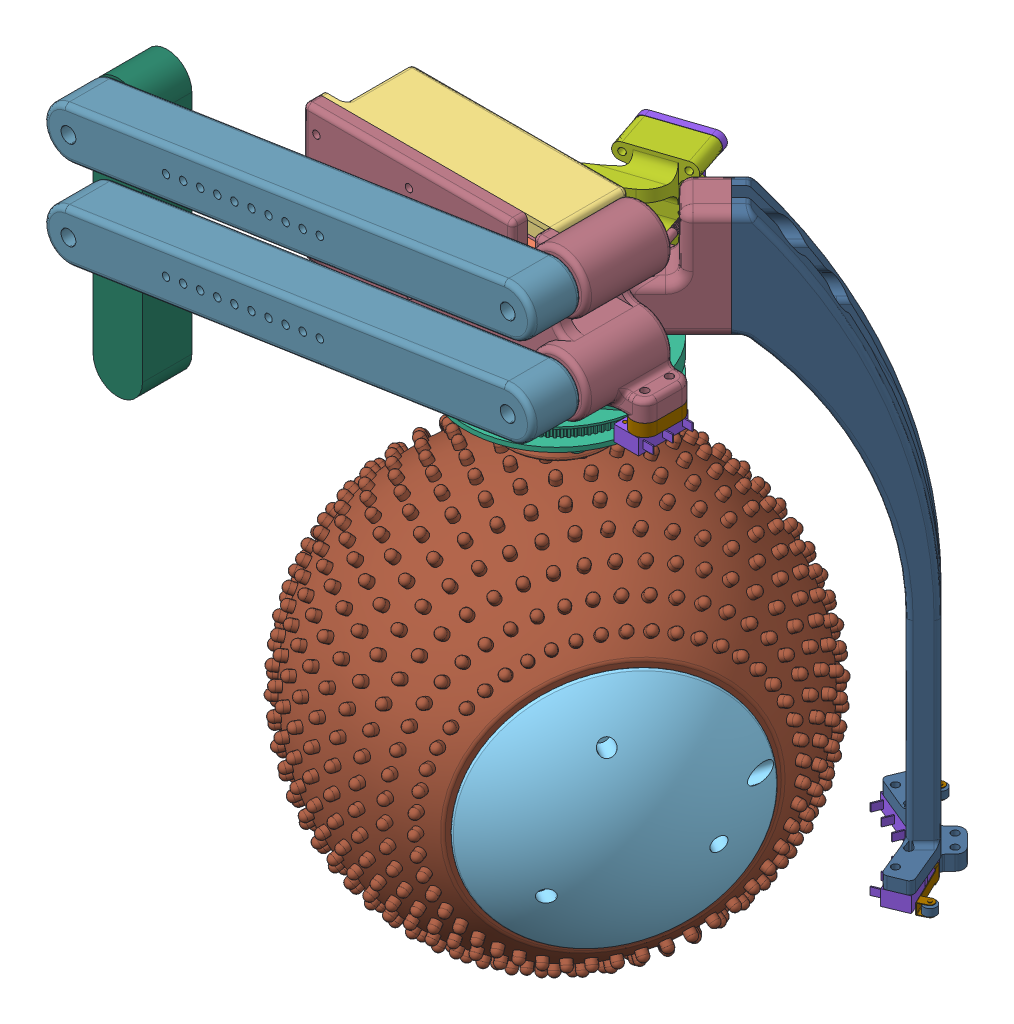
SolidWorks assembly _OmniWheel, configuration Default. Lengths in mm.
Overall size (256.7 285.35 230.93).
45 component instances, 31 part files, 111 mates.
Components (placement in the parent):
- 10mmThreadedRod-1: 10mmThreadedRod [Default] at (69.9224 -131.1915 -77.1045) x (0.033468 -0.997752 -0.058051) z (0.498338 0.067008 -0.864389) size (9.53 70 9.53)
- arduino-1: arduino [Valor predeterminado] at (146.3646 24.3085 -21) x (-1 0 0) z (0 0 -1) size (45.18 4.5 17.78)
- DriveMotor-1: DriveMotor [Default] at (151.3581 -131.1915 -30.1552) x (-0.264151 0.848701 0.458182) z (0.423893 0.528873 -0.735261) size (25 86.5 25)
- hollowThreadedNut-1: hollowThreadedNut [Default] at (108.5177 -131.1915 -54.8536) x (-0.092382 -0.982745 0.16024) z (0.490843 -0.184963 -0.851388) size (16.17 2.5 14)
- L298N Motor Driver arduino-1: L298N Motor Driver arduino [Default] at (94.2046 24.5585 -9.5) x (0 1 0) z (-1 0 0) size (43.5 26 43.5)
- n20 m4x55 encoder v2-1: n20 m4x55 encoder v2 [Default] at (132.885 2.6585 -90.2245) x (-0.316146 0 -0.948711) z (0 -1 0) size (12 10 42.21)
- slip_ring-1: slip_ring [Default] at (142.9546 -25.9415 -35) x (0.999063 0 0.043268) z (-0.043268 0 0.999063) size (23.5 17.5 23.5)
- switch_body-1: switch_body [Default] at (195.9546 -11.0665 -25) x (0 0 -1) z (0 1 0) size (20 14 6.25)
- switch_lever-1: switch_lever [Default] at (185.7475 -11.0665 -26.5353) x (0.019708 0 -0.999806) z (0 1 0) size (20 8.75 6)
- switch_wheel-1: switch_wheel [Default] at (182.2858 -10.9415 -34.8551) x (-0.999947 0 -0.010277) z (0 1 0) size (5 5 3)
- sphere_wheel-1: sphere_wheel [Default] at (142.9546 -131.1915 -35) x (-0.866337 0 -0.499461) z (0.492131 0.170683 -0.853624) size (125.5 168 168)
- motorMount-1: motorMount [Default] at (128.855 -131.1915 -43.1287) x (0.446555 -0.447916 -0.77457) z (-0.223716 -0.894076 0.388046) size (31.75 83.44 31.75)
- hollowThreadedNut-2: hollowThreadedNut [Default] at (121.686 -131.1915 -47.2618) x (-0.092382 -0.982745 0.16024) z (0.490843 -0.184963 -0.851388) size (16.17 2.5 14)
- hollowThreadedNut-4: hollowThreadedNut [Default] at (69.0994 -131.1915 -77.579) x (0.01495 -0.999552 -0.025931) z (0.499237 0.029932 -0.865948) size (16.17 2.5 14)
- hollowThreadedNut-5: hollowThreadedNut [Default] at (85.1266 -131.1915 -68.339) x (0.24973 -0.866025 -0.433168) z (0.432546 0.5 -0.75027) size (16.17 2.5 14)
- suspension_mount-1: suspension_mount [Default] at (142.9546 -2.9415 -35) x (0 0 1) z (0 1 0) size (77.43 128.5 61.17)
- suspension_bar-1: suspension_bar [Default] at (177.9546 45.0585 10) x (0.988637 0.150325 0) z (0 0 1) size (200 20 20)
- suspension_mount_body-1: suspension_mount_body [Default] at origin size (20 111.88 20)
- bearing2-1: bearing2 [Default] at (104.4026 -131.1915 -57.226) x (0.296277 0.805059 -0.513906) z (0.402095 -0.593194 -0.697452) size (25 7 25)
- Wheel_cap-1: Wheel_cap [Default] at (107.4348 -131.1915 -55.4779) x (0.08525 -0.985326 -0.147869) z (0.492131 0.170683 -0.853624) size (59.5 22.5 59.5)
- washer1-1: washer1 [Default] at (99.0963 -131.1915 -60.2852) x (-0.362018 -0.68894 0.627937) z (0.344098 -0.724818 -0.596854) size (25 2.25 25)
- SpongeRing-1: SpongeRing [Default] at (94.0066 -131.1915 -63.2195) x (-0.866337 0 -0.499461) z (0.488344 -0.20981 -0.847054) size (14 51.5 51.5)
- wheel_arm-1: wheel_arm [Default] at (85.7764 -131.1915 -67.9644) x (-0.866337 0 -0.499461) z (0.499461 0 -0.866337) size (108.38 170.79 80.42)
- suspension_bar-3: suspension_bar [Default] at (177.9546 9.0585 10) x (0.988637 0.150325 0) z (0 0 1) size (200 20 20)
- suspension_mount_lid-1: suspension_mount_lid [Default] at (117.9546 24.5585 -39) x (1 0 0) z (0 0 -1) size (96 55 30)
- bearing3-1: bearing3 [Default] at (142.9546 -10.1915 -35) x (0.997463 0 -0.071184) z (0 -1 0) size (28.5 28.5 9.5)
- 10mmThreadedRod-2: 10mmThreadedRod [short] at (142.9546 12.0585 -35) x (0.211057 0 0.977474) z (-0.977474 0 0.211057) size (9.53 36 9.53)
- hollowThreadedNut-6: hollowThreadedNut [Default] at (142.9546 15.3085 -35) x (-0.864079 0 0.503356) z (0.503356 0 0.864079) size (16.17 2.5 14)
- hollowThreadedNut-7: hollowThreadedNut [Default] at (142.9546 -4.1915 -35) x (-0.864079 0 0.503356) z (0.503356 0 0.864079) size (16.17 2.5 14)
- hollowThreadedNut-8: hollowThreadedNut [Default] at (142.9546 -16.1915 -35) x (-0.864079 0 0.503356) z (0.503356 0 0.864079) size (16.17 2.5 14)
- wheel_cap_2-1: wheel_cap_2 [Default] at (142.738 -131.1915 -35.1249) x (0.866337 0 0.499461) z (-0.08525 0.985326 0.147869) size (17.75 96.67 96.67)
- large_timing_pully-1: large_timing_pully [Default] at (142.9546 -15.9415 -35) x (-0.866337 0 -0.499461) z (0.499461 0 -0.866337) size (73.67 25.42 73.67)
- micro_gear_motor_casing_A-1: micro_gear_motor_casing_A [Default] at (132.8625 10.1585 -90.2212) x (-0.316146 0 -0.948711) z (0.948711 0 -0.316146) size (33.5 37 49.25)
- micro_gear_motor_casing_B-1: micro_gear_motor_casing_B [Default] at (130.4123 10.1585 -97.5737) x (-0.948711 0 0.316146) z (-0.316146 0 -0.948711) size (28.5 37.25 3)
- switch_spacer-1: switch_spacer [Default] at (193.4546 -5.4415 -25) x (0 0 -1) z (1 0 0) size (20 5 10)
- sensorArray_frame-1: sensorArray_frame [Default] at (178.3099 19.5585 -70.3553) x (-0.707107 0 0.707107) z (-0.707107 0 -0.707107) size (67.99 233.5 54.5)
- switch_body-2: switch_body [Default] at (200.7456 -188.5665 -113.7167) x (-0.92388 0 -0.382683) z (0 -1 0) size (20 14 6.25)
- switch_lever-2: switch_lever [Default] at (204.6761 -188.5665 -125.3908) x (-0.810364 0 -0.585927) z (0 -1 0) size (20 8.75 6)
- switch_wheel-2: switch_wheel [Default] at (200.1146 -188.5665 -133.1622) x (0.999993 0 -0.003676) z (0 -1 0) size (5 5 3)
- switch_body-3: switch_body [Default] at (221.6713 -188.5665 -92.791) x (0.382683 0 0.92388) z (0 1 0) size (20 14 6.25)
- switch_lever-3: switch_lever [Default] at (232.2619 -188.5665 -95.6971) x (0.439028 0 0.898473) z (0 1 0) size (20 8.75 6)
- switch_wheel-3: switch_wheel [Default] at (239.1409 -188.5665 -89.8762) x (-0.999993 0 -0.003746) z (0 1 0) size (5 5 3)
- 1375K107_MXL SERIES TIMING BELT PULLEY-1: 1375K107_MXL SERIES TIMING BELT PULLEY [1375K107] at (132.8625 -15.5518 -90.2212) x (0 -1 0) z (0 0 1) size (14.3 13.5 13.5)
- 90725A020_ZINC-PLATED STEEL HIGH HEX NUT-1: 90725A020_ZINC-PLATED STEEL HIGH HEX NUT [90725A020] at (144.7207 9.5585 -87.0579) x (0.900076 -0.316068 -0.299939) z (-0.299857 -0.948736 0.099924) size (5.5 3.39 6.35)
- 91290A130_BLACK-OXIDE CLASS 12.9 SOCKET HEAD CAP SCREW-1: 91290A130_BLACK-OXIDE CLASS 12.9 SOCKET HEAD CAP SCREW [91290A130] at (142.4135 9.5585 -93.9816) x (-0.851007 -0.442001 0.283587) z (-0.316146 0 -0.948711) size (5.5 5.5 33.26)
Mates (geometry in assembly coordinates):
- Concentric1: concentric aligned: cylinder of DriveMotor-1 through (195.1081 -131.1915 -4.9325) axis (-0.866337 0 -0.499461) radius 12.5; cylinder of sphere_wheel-1 through (206.1972 -131.1915 1.4606) axis (-0.866337 0 -0.499461) radius 25
- Concentric2: concentric aligned: cylinder of DriveMotor-1 through (171.717 -131.1915 -18.4179) axis (-0.866337 0 -0.499461) radius 12.2; cylinder of motorMount-1 through (181.8869 -131.1915 -12.5547) axis (-0.866337 0 -0.499461) radius 12.7
- Concentric4: concentric aligned: cylinder of 10mmThreadedRod-1 through (13.6105 -131.1915 -109.5695) axis (0.866337 0 0.499461) radius 4.7625; cylinder of motorMount-1 through (109.6006 -131.1915 -54.2292) axis (0.866337 0 0.499461) radius 4.7625
- Concentric5: concentric aligned: cylinder of 10mmThreadedRod-1 through (13.6105 -131.1915 -109.5695) axis (0.866337 0 0.499461) radius 4.7625; cylinder of hollowThreadedNut-1 through (107.4348 -131.1915 -55.4779) axis (0.866337 0 0.499461) radius 5
- Concentric6: concentric aligned: cylinder of 10mmThreadedRod-1 through (13.6105 -131.1915 -109.5695) axis (0.866337 0 0.499461) radius 4.7625; cylinder of hollowThreadedNut-2 through (120.6031 -131.1915 -47.8861) axis (0.866337 0 0.499461) radius 5
- Coincident1: coincident anti-aligned: plane of motorMount-1 through (120.6031 -131.1915 -47.8861) normal (0.866337 0 0.499461); plane of hollowThreadedNut-2 through (120.6031 -131.1915 -47.8861) normal (-0.866337 0 -0.499461)
- Coincident2: coincident anti-aligned: plane of hollowThreadedNut-1 through (109.6006 -131.1915 -54.2292) normal (0.866337 0 0.499461); plane of motorMount-1 through (109.6006 -131.1915 -54.2292) normal (-0.866337 0 -0.499461)
- Concentric9: concentric aligned: cylinder of 10mmThreadedRod-1 through (13.6105 -131.1915 -109.5695) axis (0.866337 0 0.499461) radius 4.7625; cylinder of hollowThreadedNut-4 through (68.0165 -131.1915 -78.2033) axis (0.866337 0 0.499461) radius 5
- Concentric10: concentric aligned: cylinder of 10mmThreadedRod-1 through (13.6105 -131.1915 -109.5695) axis (0.866337 0 0.499461) radius 4.7625; cylinder of hollowThreadedNut-5 through (84.0437 -131.1915 -68.9633) axis (0.866337 0 0.499461) radius 5
- Concentric11: concentric aligned: cylinder of switch_body-1 through (187.4546 -7.9415 -18) axis (0 -1 0) radius 0.75; cylinder of switch_lever-1 through (187.4546 -9.0665 -18) axis (0 -1 0) radius 1.5
- Width1: width anti-aligned: plane of switch_body-1 through (195.9546 -14.1915 -25) normal (0 -1 0); plane of switch_body-1 through (195.9546 -7.9415 -25) normal (0 1 0); plane of switch_lever-1 through (185.7345 -13.8165 -19.5342) normal (0 1 0); plane of switch_lever-1 through (185.7345 -8.3165 -19.5342) normal (0 -1 0)
- Concentric12: concentric aligned: cylinder of switch_lever-1 through (182.2858 -8.5665 -34.8551) axis (0 -1 0) radius 0.75; cylinder of switch_wheel-1 through (182.2858 -9.4415 -34.8551) axis (0 -1 0) radius 2.5
- Concentric18: concentric anti-aligned: cylinder of 10mmThreadedRod-1 through (13.6105 -131.1915 -109.5695) axis (0.866337 0 0.499461) radius 4.7625; cylinder of bearing2-1 through (107.4348 -131.1915 -55.4779) axis (-0.866337 0 -0.499461) radius 5
- Coincident24: coincident anti-aligned: plane of hollowThreadedNut-1 through (107.4348 -131.1915 -55.4779) normal (-0.866337 0 -0.499461); plane of bearing2-1 through (107.4348 -131.1915 -55.4779) normal (0.866337 0 0.499461)
- Concentric19: concentric anti-aligned: cylinder of bearing2-1 through (107.4348 -131.1915 -55.4779) axis (-0.866337 0 -0.499461) radius 11; cylinder of Wheel_cap-1 through (87.9422 -131.1915 -66.7157) axis (0.866337 0 0.499461) radius 11.125
- Coincident25: coincident anti-aligned: plane of bearing2-1 through (106.1353 -131.1915 -56.2271) normal (-0.866337 0 -0.499461); plane of Wheel_cap-1 through (106.1353 -131.1915 -56.2271) normal (0.866337 0 0.499461)
- Parallel1: parallel anti-aligned: plane of sphere_wheel-1 through (142.9546 -131.1915 -35) normal (-0.08525 0.985326 0.147869); plane of Wheel_cap-1 through (107.4348 -131.1915 -55.4779) normal (0.08525 -0.985326 -0.147869)
- Concentric20: concentric aligned: cylinder of 10mmThreadedRod-1 through (13.6105 -131.1915 -109.5695) axis (0.866337 0 0.499461) radius 4.7625; cylinder of washer1-1 through (98.1217 -131.1915 -60.8471) axis (0.866337 0 0.499461) radius 5.75
- Coincident26: coincident anti-aligned: plane of Wheel_cap-1 through (100.0709 -131.1915 -59.7233) normal (-0.866337 0 -0.499461); plane of washer1-1 through (100.0709 -131.1915 -59.7233) normal (0.866337 0 0.499461)
- Tangent1: tangent anti-aligned: cylinder of Wheel_cap-1 through (118.1777 -126.1135 -83.1216) axis (-0.492131 -0.170683 0.853624) radius 4; plane of SpongeRing-1 through (101.538 -117.5031 -62.268) normal (0.866337 0 0.499461)
- Concentric21: concentric aligned: cylinder of Wheel_cap-1 through (105.269 -131.1915 -56.7265) axis (-0.866337 0 -0.499461) radius 26; cylinder of SpongeRing-1 through (94.0066 -131.1915 -63.2195) axis (-0.866337 0 -0.499461) radius 25.75
- Concentric22: concentric aligned: cylinder of 10mmThreadedRod-1 through (13.6105 -131.1915 -109.5695) axis (0.866337 0 0.499461) radius 4.7625; cylinder of wheel_arm-1 through (73.6477 -131.1915 -74.9568) axis (0.866337 0 0.499461) radius 4.7625
- Concentric24: concentric: sphere of sphere_wheel-1; sphere of wheel_arm-1
- Parallel2: parallel anti-aligned: plane of hollowThreadedNut-5 through (82.0252 -124.1915 -65.4621) normal (0 1 0); plane of wheel_arm-1 through (86.0983 -124.0665 -72.5271) normal (0 -1 0)
- Coincident27: coincident anti-aligned: plane of hollowThreadedNut-5 through (84.0437 -131.1915 -68.9633) normal (-0.866337 0 -0.499461); plane of wheel_arm-1 through (84.0437 -131.1915 -68.9633) normal (0.866337 0 0.499461)
- Concentric26: concentric anti-aligned: cylinder of slip_ring-1 through (142.9546 -34.6915 -35) axis (0 -1 0) radius 6.25; cylinder of wheel_arm-1 through (142.9546 -39.1915 -35) axis (0 1 0) radius 20
- Distance2: distance = 12 mm anti-aligned: plane of DriveMotor-1 through (130.9991 -131.1915 -41.8926) normal (-0.866337 0 -0.499461); plane of motorMount-1 through (120.6031 -131.1915 -47.8861) normal (0.866337 0 0.499461)
- Coincident28: coincident anti-aligned: plane of hollowThreadedNut-4 through (70.1823 -131.1915 -76.9547) normal (0.866337 0 0.499461); plane of wheel_arm-1 through (70.1823 -131.1915 -76.9547) normal (-0.866337 0 -0.499461)
- Distance3: distance = 4 mm aligned: plane of hollowThreadedNut-2 through (122.769 -131.1915 -46.6374) normal (0.866337 0 0.499461); plane of 10mmThreadedRod-1 through (126.2343 -131.1915 -44.6396) normal (0.866337 0 0.499461)
- Coincident30: coincident anti-aligned: plane of slip_ring-1 through (131.2156 -21.1915 -35.5084) normal (0 -1 0); plane of wheel_arm-1 through (142.9546 -21.1915 -35) normal (0 1 0)
- Concentric28: concentric anti-aligned: cylinder of suspension_mount-1 through (142.9546 57.0585 -35) axis (0 -1 0) radius 20; cylinder of wheel_arm-1 through (142.9546 -39.1915 -35) axis (0 1 0) radius 20
- Parallel4: parallel aligned: cylinder of n20 m4x55 encoder v2-1 through (132.865 -0.8148 -90.2195) axis (0 -1 0) radius 1.954; cylinder of suspension_mount-1 through (142.9546 57.0585 -35) axis (0 -1 0) radius 20
- Parallel5: parallel aligned: plane of suspension_mount-1 through (142.9546 -2.9415 -35) normal (0 0 1)
- Concentric33: concentric aligned: cylinder of suspension_mount-1 through (177.9546 45.0585 -15) axis (0 0 -1) radius 3; cylinder of suspension_bar-1 through (177.9546 45.0585 20) axis (0 0 -1) radius 3
- Coincident32: coincident aligned: plane of suspension_bar-1 through (0 18 20) normal (0 0 1); plane of suspension_bar-3 through (0 -18 20) normal (0 0 1)
- Concentric42: concentric aligned: cylinder of suspension_mount-1 through (177.9546 9.0585 -15) axis (0 0 -1) radius 3; cylinder of suspension_bar-3 through (177.9546 9.0585 20) axis (0 0 -1) radius 3
- Coincident33: coordinate: point of suspension_mount_body-1
- Concentric45: concentric anti-aligned: cylinder of suspension_bar-1 through (0 18 20) axis (0 0 -1) radius 3; cylinder of suspension_mount_body-1 through (0 18 -20) axis (0 0 1) radius 3
- Concentric46: concentric anti-aligned: cylinder of suspension_mount_body-1 through (0 -18 -20) axis (0 0 1) radius 3; cylinder of suspension_bar-3 through (0 -18 20) axis (0 0 -1) radius 3
- Coincident34: coincident anti-aligned: plane of suspension_mount-1 through (177.9546 45.0585 0) normal (0 0 1); plane of suspension_bar-1 through (0 18 0) normal (0 0 -1)
- Coincident35: coincident anti-aligned: plane of suspension_mount_body-1 through (0 18 0) normal (0 0 1); plane of suspension_bar-3 through (0 -18 0) normal (0 0 -1)
- Parallel8: parallel aligned: plane of L298N Motor Driver arduino-1 through (94.2046 24.5585 -11) normal (0 0 -1); plane of suspension_mount-1 through (177.9546 45.0585 -7) normal (0 0 -1)
- Parallel9: parallel aligned: plane of L298N Motor Driver arduino-1 through (72.4546 2.8085 -11) normal (0 -1 0); plane of suspension_mount-1 through (142.9546 -2.9415 -35) normal (0 -1 0)
- Parallel11: parallel aligned: plane of arduino-1 through (146.3646 25.3085 -21) normal (0 1 0); plane of suspension_mount-1 through (165.9546 17.0585 -55) normal (0 1 0)
- Concentric47: concentric anti-aligned: cylinder of L298N Motor Driver arduino-1 through (112.9546 43.3085 -11) axis (0 0 1) radius 1.5; cylinder of suspension_mount-1 through (112.9546 43.3085 0) axis (0 0 -1) radius 1.5
- Concentric48: concentric anti-aligned: cylinder of L298N Motor Driver arduino-1 through (75.4546 5.8085 -11) axis (0 0 1) radius 1.5; cylinder of suspension_mount-1 through (75.4546 5.8085 0) axis (0 0 -1) radius 1.5
- Coincident36: coincident anti-aligned: plane of L298N Motor Driver arduino-1 through (94.2046 24.5585 -9.5) normal (0 0 1); plane of suspension_mount-1 through (75.4546 5.8085 -9.5) normal (0 0 -1)
- Width3: width anti-aligned: plane of suspension_mount-1 through (167.9546 23.5585 -30) normal (0 0 1); plane of arduino-1 through (167.9546 23.5585 -12) normal (0 0 -1); plane of suspension_mount-1 through (167.9546 25.3085 -29.89) normal (0 0 -1); plane of arduino-1 through (167.9546 25.3085 -12.11) normal (0 0 1)
- Coincident37: coincident anti-aligned: plane of arduino-1 through (167.9546 25.3085 -29.89) normal (1 0 0); plane of suspension_mount-1 through (167.9546 -2.9415 -35) normal (-1 0 0)
- Width4: width aligned: plane of suspension_mount-1 through (189.9546 24.8085 -25.25) normal (0 1 0); plane of arduino-1 through (189.9546 29.3085 -25.25) normal (0 -1 0); plane of suspension_mount-1 through (146.3646 28.8085 -21) normal (0 1 0); plane of arduino-1 through (146.3646 25.3085 -21) normal (0 -1 0)
- Coincident38: coincident aligned: plane of suspension_mount-1 through (168.2078 52.0585 -7) normal (0 1 0); plane of suspension_mount_lid-1 through (69.9546 52.0585 -41) normal (0 1 0)
- Coincident39: coincident aligned: plane of suspension_mount-1 through (69.9546 52.0585 -7) normal (-1 0 0); plane of suspension_mount_lid-1 through (69.9546 52.0585 -41) normal (-1 0 0)
- Coincident40: coincident anti-aligned: plane of suspension_mount-1 through (158.9546 42.0585 -11) normal (0 0 -1); plane of suspension_mount_lid-1 through (117.9546 24.5585 -11) normal (0 0 1)
- Concentric49: concentric aligned: cylinder of wheel_arm-1 through (142.9546 -39.1915 -35) axis (0 1 0) radius 20; cylinder of bearing3-1 through (142.9546 -14.9415 -35) axis (0 1 0) radius 14.25
- Concentric50: concentric anti-aligned: cylinder of suspension_mount-1 through (142.9546 -2.9415 -35) axis (0 1 0) radius 4.7625; cylinder of 10mmThreadedRod-2 through (142.9546 77.0585 -35) axis (0 -1 0) radius 4.7625
- Concentric51: concentric anti-aligned: cylinder of 10mmThreadedRod-2 through (142.9546 77.0585 -35) axis (0 -1 0) radius 4.7625; cylinder of hollowThreadedNut-6 through (142.9546 14.0585 -35) axis (0 1 0) radius 5
- Coincident42: coincident anti-aligned: plane of suspension_mount-1 through (142.9546 14.0585 -35) normal (0 1 0); plane of hollowThreadedNut-6 through (142.9546 14.0585 -35) normal (0 -1 0)
- Coincident43: coincident aligned: plane of suspension_mount-1 through (165.9546 17.0585 -55) normal (0 1 0); plane of 10mmThreadedRod-2 through (157.158 17.0585 -42.9391) normal (0 1 0)
- Concentric52: concentric anti-aligned: cylinder of 10mmThreadedRod-2 through (142.9546 77.0585 -35) axis (0 -1 0) radius 4.7625; cylinder of hollowThreadedNut-7 through (142.9546 -5.4415 -35) axis (0 1 0) radius 5
- Coincident44: coincident anti-aligned: plane of suspension_mount-1 through (142.9546 -2.9415 -35) normal (0 -1 0); plane of hollowThreadedNut-7 through (142.9546 -2.9415 -35) normal (0 1 0)
- Coincident45: coincident anti-aligned: plane of bearing3-1 through (142.9546 -5.4415 -35) normal (0 1 0); plane of hollowThreadedNut-7 through (142.9546 -5.4415 -35) normal (0 -1 0)
- Concentric53: concentric anti-aligned: cylinder of 10mmThreadedRod-2 through (142.9546 77.0585 -35) axis (0 -1 0) radius 4.7625; cylinder of hollowThreadedNut-8 through (142.9546 -17.4415 -35) axis (0 1 0) radius 5
- Coincident46: coincident anti-aligned: plane of bearing3-1 through (142.9546 -14.9415 -35) normal (0 -1 0); plane of hollowThreadedNut-8 through (142.9546 -14.9415 -35) normal (0 1 0)
- Coincident47: coincident anti-aligned: plane of wheel_arm-1 through (125.6081 -14.9415 -39.8063) normal (0 1 0); plane of bearing3-1 through (142.9546 -14.9415 -35) normal (0 -1 0)
- Coincident48: coincident anti-aligned: plane of sphere_wheel-1 through (196.6675 -131.1915 -4.0334) normal (0.866337 0 0.499461); plane of wheel_cap_2-1 through (221.3965 -122.6149 -46.927) normal (-0.866337 0 -0.499461)
- Concentric54: concentric aligned: cylinder of sphere_wheel-1 through (206.1972 -131.1915 1.4606) axis (-0.866337 0 -0.499461) radius 25; cylinder of wheel_cap_2-1 through (209.6625 -131.1915 3.4585) axis (-0.866337 0 -0.499461) radius 2
- Parallel12: parallel aligned: plane of sphere_wheel-1 through (142.9546 -131.1915 -35) normal (-0.08525 0.985326 0.147869); plane of wheel_cap_2-1 through (142.738 -131.1915 -35.1249) normal (-0.08525 0.985326 0.147869)
- Concentric55: concentric anti-aligned: cylinder of wheel_arm-1 through (142.9546 -39.1915 -35) axis (0 1 0) radius 20; cylinder of large_timing_pully-1 through (142.9546 -15.9415 -35) axis (0 -1 0) radius 20.25
- Parallel13: parallel aligned: plane of wheel_arm-1 through (85.7764 -131.1915 -67.9644) normal (0.499461 0 -0.866337); plane of large_timing_pully-1 through (142.9546 -15.9415 -35) normal (0.499461 0 -0.866337)
- Parallel14: parallel aligned: plane of n20 m4x55 encoder v2-1; plane of micro_gear_motor_casing_A_rev2-1
- Concentric58: concentric anti-aligned: cylinder of n20 m4x55 encoder v2-1 through (132.865 -0.8148 -90.2195) axis (0 -1 0) radius 1.954; cylinder of micro_gear_motor_casing_A_rev2-1 through (132.865 -10.5776 -90.2195) axis (0 1 0) radius 6.4971
- Coincident49: coincident anti-aligned: plane of n20 m4x55 encoder v2-1 through (132.8875 -6.3415 -90.2228) normal (0 -1 0); plane of micro_gear_motor_casing_A_rev2-1 through (132.865 -6.3415 -90.2195) normal (0 1 0)
- Distance4: distance = 3.5 mm aligned: plane of wheel_arm-1 through (125.6081 -4.9415 -39.8063) normal (0 1 0); plane of large_timing_pully-1 through (125.4113 -8.4415 -45.1141) normal (0 1 0)
- Concentric59: concentric anti-aligned: cylinder of micro_gear_motor_casing_A_rev2-1 through (125.2736 -4.9665 -78.9947) axis (-0.316068 0 -0.948736) radius 1.4; cylinder of micro_gear_motor_casing_B-1 through (119.7424 -4.9665 -95.5976) axis (0.316068 0 0.948736) radius 1.5
- Concentric60: concentric anti-aligned: cylinder of micro_gear_motor_casing_A_rev2-1 through (145.6715 25.2835 -85.7901) axis (-0.316068 0 -0.948736) radius 1.4; cylinder of micro_gear_motor_casing_B-1 through (140.1403 25.2835 -102.393) axis (0.316068 0 0.948736) radius 1.5
- Coincident50: coincident anti-aligned: plane of micro_gear_motor_casing_A_rev2-1; plane of micro_gear_motor_casing_B-1
- Coincident51: coincident anti-aligned: plane of sphere_wheel-1 through (104.8773 -101.6317 -51.0418) normal (-0.866337 0 -0.499461); plane of Wheel_cap-1 through (107.4348 -131.1915 -55.4779) normal (0.866337 0 0.499461)
- Concentric61: concentric aligned: cylinder of suspension_mount-1 through (111.4354 2.0585 -59.628) axis (0 1 0) radius 2; cylinder of micro_gear_motor_casing_A_rev2-1 through (111.4354 -2.9415 -59.628) axis (0 1 0) radius 2
- Width5: width aligned: plane of suspension_mount-1 through (165.9546 17.0585 -55) normal (0 1 0); plane of micro_gear_motor_casing_A_rev2-1 through (142.9546 2.0585 -35) normal (0 -1 0); plane of suspension_mount-1 through (132.865 17.3085 -90.2195) normal (0 -1 0); plane of micro_gear_motor_casing_A_rev2-1 through (132.865 1.8085 -90.2195) normal (0 1 0)
- Concentric62: concentric aligned: cylinder of switch_body-1 through (193.4546 -7.9415 -30) axis (0 -1 0) radius 1.5; cylinder of suspension_mount-1 through (193.4546 5.0585 -30) axis (0 -1 0) radius 1.5
- Concentric63: concentric aligned: cylinder of switch_body-1 through (193.4546 -7.9415 -20) axis (0 -1 0) radius 1.5; cylinder of suspension_mount-1 through (193.4546 5.0585 -20) axis (0 -1 0) radius 1.5
- Concentric64: concentric aligned: cylinder of suspension_mount-1 through (193.4546 5.0585 -20) axis (0 -1 0) radius 1.5; cylinder of switch_spacer-1 through (193.4546 -2.9415 -20) axis (0 -1 0) radius 1.6
- Concentric65: concentric aligned: cylinder of suspension_mount-1 through (193.4546 5.0585 -30) axis (0 -1 0) radius 1.5; cylinder of switch_spacer-1 through (193.4546 -2.9415 -30) axis (0 -1 0) radius 1.6
- Coincident52: coincident anti-aligned: plane of suspension_mount-1 through (142.9546 -2.9415 -35) normal (0 -1 0); plane of switch_spacer-1 through (193.4546 -2.9415 -30) normal (0 1 0)
- Coincident53: coincident anti-aligned: plane of switch_body-1 through (195.9546 -7.9415 -25) normal (0 1 0); plane of switch_spacer-1 through (193.4546 -7.9415 -30) normal (0 -1 0)
- PathMate2: path: circle of switch_wheel-1; curve of large_timing_pully-1
- PathMate3: path: unknown of switch_wheel-1; edge_curve of large_timing_pully-1
- Coincident54: coincident anti-aligned: plane of suspension_mount-1 through (185.381 -2.9415 -63.2843) normal (0.707107 0 -0.707107); plane of sensorArray_frame-1 through (171.2389 -2.9415 -77.4264) normal (-0.707107 0 0.707107)
- Width6: width aligned: plane of sensorArray_frame-1 through (114.6703 -101.3031 -20.8579) normal (-0.707107 0 -0.707107); plane of sensorArray_frame-1 through (128.8125 -101.3031 -6.7157) normal (0.707107 0 0.707107); plane of suspension_mount-1 through (148.131 -2.9415 -54.3185) normal (-0.707107 0 -0.707107); plane of suspension_mount-1 through (162.2731 -2.9415 -40.1764) normal (0.707107 0 0.707107)
- Coincident56: coincident aligned: plane of suspension_mount-1 through (174.7744 42.0585 -52.6777) normal (0 1 0); plane of sensorArray_frame-1 through (171.2389 42.0585 -77.4264) normal (0 1 0)
- Concentric66: concentric aligned: cylinder of switch_body-2 through (210.4656 -191.6915 -118.8909) axis (0 1 0) radius 0.75; cylinder of switch_lever-2 through (210.4656 -191.3165 -118.8909) axis (0 1 0) radius 1.5
- Concentric67: concentric aligned: cylinder of switch_lever-2 through (200.1146 -191.0665 -133.1622) axis (0 1 0) radius 0.75; cylinder of switch_wheel-2 through (200.1146 -190.0665 -133.1622) axis (0 1 0) radius 2.5
- Width7: width aligned: plane of switch_lever-2 through (199.3355 -190.8165 -129.098) normal (0 -1 0); plane of switch_lever-2 through (199.3355 -186.3165 -129.098) normal (0 1 0); plane of switch_wheel-2 through (200.1146 -190.0665 -133.1622) normal (0 -1 0); plane of switch_wheel-2 through (200.1146 -187.0665 -133.1622) normal (0 1 0)
- Width8: width anti-aligned: plane of switch_body-2 through (200.7456 -185.4415 -113.7167) normal (0 1 0); plane of switch_body-2 through (200.7456 -191.6915 -113.7167) normal (0 -1 0); plane of switch_lever-2 through (210.2754 -185.8165 -121.188) normal (0 -1 0); plane of switch_lever-2 through (210.2754 -191.3165 -121.188) normal (0 1 0)
- Coincident57: coincident anti-aligned: plane of sensorArray_frame-1 through (206.5942 -185.4415 -112.7817) normal (0 -1 0); plane of switch_body-2 through (200.7456 -185.4415 -113.7167) normal (0 1 0)
- Parallel15: parallel aligned: plane of sensorArray_frame-1 through (191.5068 -180.4415 -117.5436) normal (-0.382683 0 0.92388); plane of switch_body-2 through (191.5068 -191.6915 -117.5436) normal (-0.382683 0 0.92388)
- Coincident58: coincident aligned: plane of sensorArray_frame-1 through (195.3337 -180.4415 -126.7824) normal (-0.92388 0 -0.382683); plane of switch_body-2 through (195.1423 -191.6915 -126.3204) normal (-0.92388 0 -0.382683)
- Coincident59: coincident aligned: plane of sensorArray_frame-1 through (214.4306 -180.4415 -118.8721) normal (0.382683 0 -0.92388); plane of switch_body-2 through (213.8112 -191.6915 -119.1287) normal (0.382683 0 -0.92388)
- Concentric68: concentric aligned: cylinder of switch_lever-3 through (239.1409 -186.0665 -89.8762) axis (0 -1 0) radius 0.75; cylinder of switch_wheel-3 through (239.1409 -187.0665 -89.8762) axis (0 -1 0) radius 2.5
- Width9: width aligned: plane of switch_lever-3 through (235.0033 -186.3165 -89.8022) normal (0 1 0); plane of switch_lever-3 through (235.0033 -190.8165 -89.8022) normal (0 -1 0); plane of switch_wheel-3 through (239.1409 -187.0665 -89.8762) normal (0 1 0); plane of switch_wheel-3 through (239.1409 -190.0665 -89.8762) normal (0 -1 0)
- Concentric69: concentric aligned: cylinder of switch_body-3 through (226.8455 -185.4415 -102.511) axis (0 -1 0) radius 0.75; cylinder of switch_lever-3 through (226.8455 -186.5665 -102.511) axis (0 -1 0) radius 1.5
- Width10: width aligned: plane of switch_body-3 through (221.6713 -191.6915 -92.791) normal (0 -1 0); plane of switch_body-3 through (221.6713 -185.4415 -92.791) normal (0 1 0); plane of switch_lever-3 through (226.1564 -191.5665 -100.5047) normal (0 -1 0); plane of switch_lever-3 through (226.1564 -185.5665 -100.5047) normal (0 1 0)
- Coincident60: coincident anti-aligned: plane of sensorArray_frame-1 through (206.5942 -185.4415 -112.7817) normal (0 -1 0); plane of switch_body-3 through (221.6713 -185.4415 -92.791) normal (0 1 0)
- Concentric70: concentric aligned: cylinder of sensorArray_frame-1 through (222.0676 -180.4415 -98.3671) axis (0 -1 0) radius 1.5; cylinder of switch_body-3 through (222.0676 -185.4415 -98.3671) axis (0 -1 0) radius 1.5
- Concentric71: concentric aligned: cylinder of sensorArray_frame-1 through (225.8945 -180.4415 -89.1283) axis (0 -1 0) radius 1.5; cylinder of switch_body-3 through (225.8945 -185.4415 -89.1283) axis (0 -1 0) radius 1.5
- Concentric72: concentric anti-aligned: circle of n20 m4x55 encoder v2-1; circle of 1375K101_MXL SERIES TIMING BELT PULLEY-1
- Coincident65: coincident aligned: plane of large_timing_pully-1 through (114.6821 -21.6018 -51.2996) normal (0 1 0); plane of 1375K107_MXL SERIES TIMING BELT PULLEY-1 through (128.315 -21.6018 -90.2195) normal (0 1 0)
- Concentric73: concentric anti-aligned: circle of micro_gear_motor_casing_A_rev2-1; circle of 90725A020_ZINC-PLATED STEEL HIGH HEX NUT-1
- Coincident67: coincident anti-aligned: plane of micro_gear_motor_casing_A_rev2-1; plane of 90725A020_ZINC-PLATED STEEL HIGH HEX NUT-1
- Coincident71: coincident anti-aligned: plane of suspension_mount-1 through (158.2466 9.5585 -64.4738) normal (-0.316146 0 -0.948711); plane of 91290A130_BLACK-OXIDE CLASS 12.9 SOCKET HEAD CAP SCREW-1 through (152.8463 9.5585 -62.6742) normal (0.316146 0 0.948711)
- Concentric75: concentric aligned: circle of micro_gear_motor_casing_A-1; circle of 91290A130_BLACK-OXIDE CLASS 12.9 SOCKET HEAD CAP SCREW-1
